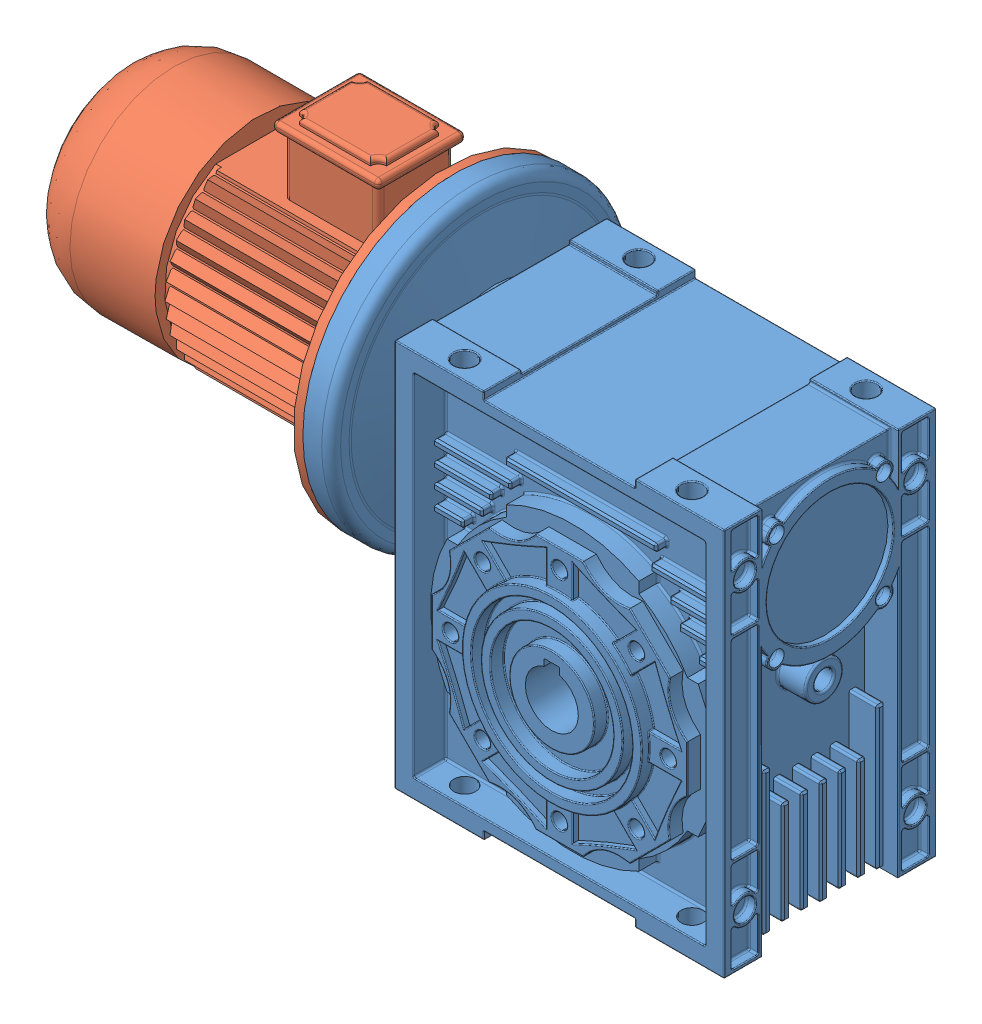
SolidWorks assembly Мотор-редуктор MNRV-075, configuration По умолчанию. Lengths in mm.
Overall size (376.62 243.4 160).
2 component instances, 2 part files, 3 mates.
Components (placement in the parent):
- NMRV075-1: NMRV075 [По умолчанию] at (-45.4345 -130.9075 185) size (198.62 241 160)
- Двигатель на NMRV-075-1: Двигатель на NMRV-075 [По умолчанию] at (42.1435 178.7335 241) size (178 162.4 160)
Mates (geometry in assembly coordinates):
- Совпадение1: coincident: plane of NMRV075-1 through (-69.9345 30.0925 241) normal (-1 0 0); plane of Двигатель на NMRV-075-1 through (-69.9345 30.0925 241) normal (1 0 0)
- Концентричный1: concentric: cylinder of NMRV075-1 through (-54.9345 30.0925 241) axis (-1 0 0) radius 80; cylinder of Двигатель на NMRV-075-1 through (-69.9345 30.0925 241) axis (1 0 0) radius 80
- Параллельность2: parallel aligned: plane of NMRV075-1 through (-45.4345 72.0925 241) normal (0 1 0); plane of Двигатель на NMRV-075-1 through (42.1435 112.4956 241) normal (0 1 0)
